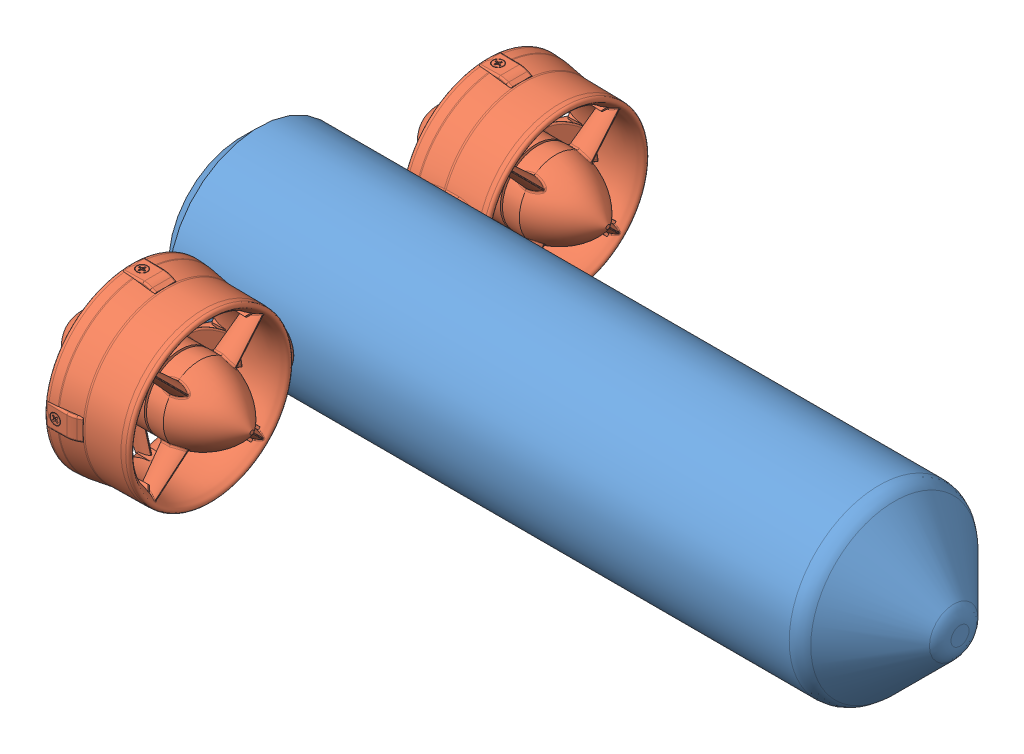
SolidWorks assembly auv_d-assembly, configuration Water. Lengths in mm.
Overall size (467.31 234.82 294.71).
3 component instances, 2 part files, 6 mates.
Components (placement in the parent):
- body-1: body [water] at origin size (400 100 100)
- thruster-1: thruster [Water] at (-140 0 99) x (0 1 0) z (1 0 0) size (96.71 97.51 100.86)
- thruster-2: thruster [Water] at (-140 0 -99) x (0 -1 0) z (1 0 0) size (96.71 97.51 100.86)
Mates (geometry in assembly coordinates):
- Coincident2: coincident aligned: plane of T100-ASM-CW-THRUSTER-R1-1 through (-140 0 99) normal (0 1 0)
- Coincident3: coincident anti-aligned: plane of T100-ASM-CW-THRUSTER-R1-1 through (-140 0 99) normal (1 0 0)
- Tangent1: tangent anti-aligned: cylinder of body-1 through (200 0 0) axis (-1 0 0) radius 50; plane of T100-ASM-CW-THRUSTER-R1-1 through (-134.7482 0 50) normal (0 0 -1)
- Coincident4: coincident anti-aligned: plane of T100-ASM-CW-THRUSTER-R1-2 through (-140 0 -99) normal (0 -1 0)
- Coincident6: coincident anti-aligned: plane of T100-ASM-CW-THRUSTER-R1-2 through (-140 0 -99) normal (1 0 0)
- Tangent2: tangent anti-aligned: cylinder of body-1 through (200 0 0) axis (-1 0 0) radius 50; plane of T100-ASM-CW-THRUSTER-R1-2 through (-134.7482 0 -50) normal (0 0 1)
